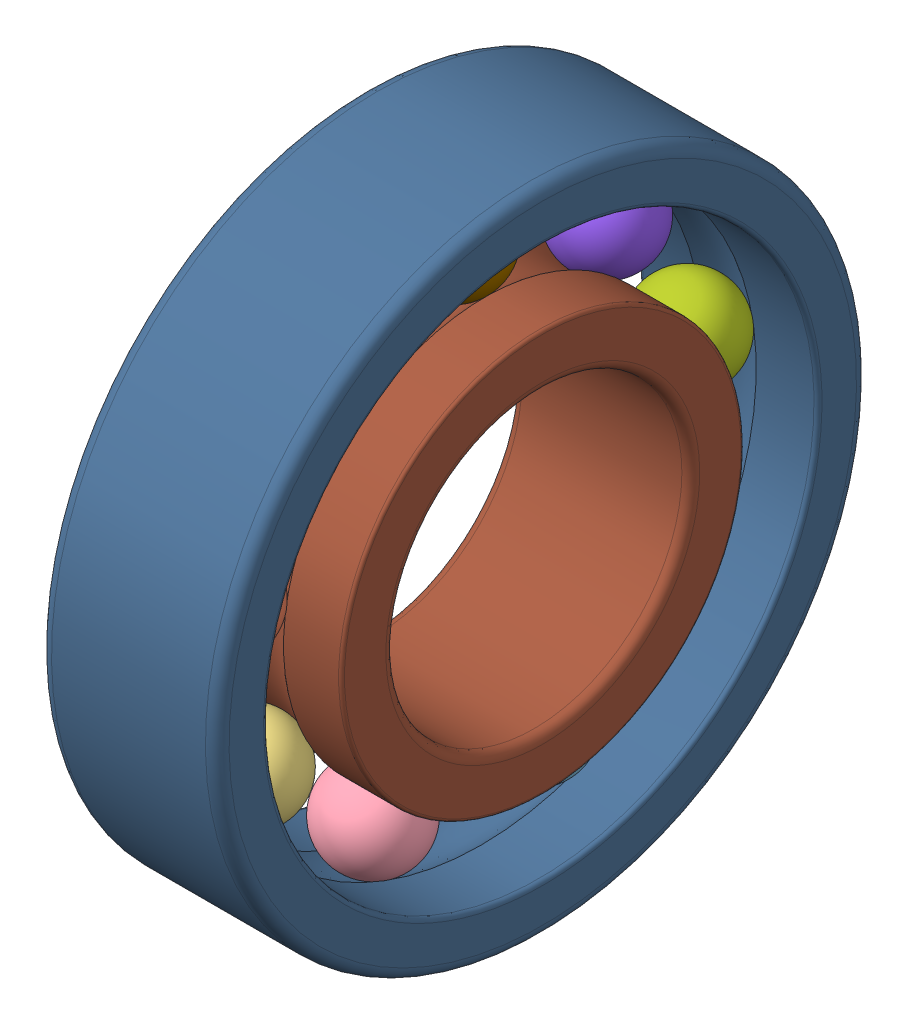
SolidWorks assembly ballBearing, configuration Défaut. Lengths in mm.
Overall size (3.01 11 11).
11 component instances, 11 part files, 1 mates.
Components (placement in the parent):
- ball1-1: ball1 [Défaut] at (1.5 3.0642 2.5712) size (1.96 2.07 2.07)
- ball2-1: ball2 [Défaut] at (1.5 0.6946 3.9392) size (2.15 2.2 2.14)
- ball3-1: ball3 [Défaut] at (1.5 -2 3.4641) size (1.97 2.11 2.11)
- ball4-1: ball4 [Défaut] at (1.5 -3.7588 1.3681) size (2.08 2.02 2.1)
- ball5-1: ball5 [Défaut] at (1.5 -3.7588 -1.3681) size (1.97 2.13 2.17)
- ball6-1: ball6 [Défaut] at (1.5 -2 -3.4641) size (2.07 2.2 2.04)
- ball7-1: ball7 [Défaut] at (1.5 0.6946 -3.9392) size (2.09 2.05 2.22)
- ball8-1: ball8 [Défaut] at (1.5 3.0642 -2.5712) size (2.02 2.17 2.18)
- ball9-1: ball9 [Défaut] at (1.5 4 0) size (2.21 2.22 2.24)
- external_ring-1: external_ring [Défaut] at (1.5 0 0) size (3.01 11 11)
- internal_ring-1: internal_ring [Défaut] at (1.5 0 0) size (3.01 6.8 6.8)
Mates (geometry in assembly coordinates):
- Coïncidente1: coincident aligned: plane of external_ring-1 through (0 5.3 0) normal (-1 0 0); plane of internal_ring-1 through (0 3.35 0) normal (-1 0 0)
